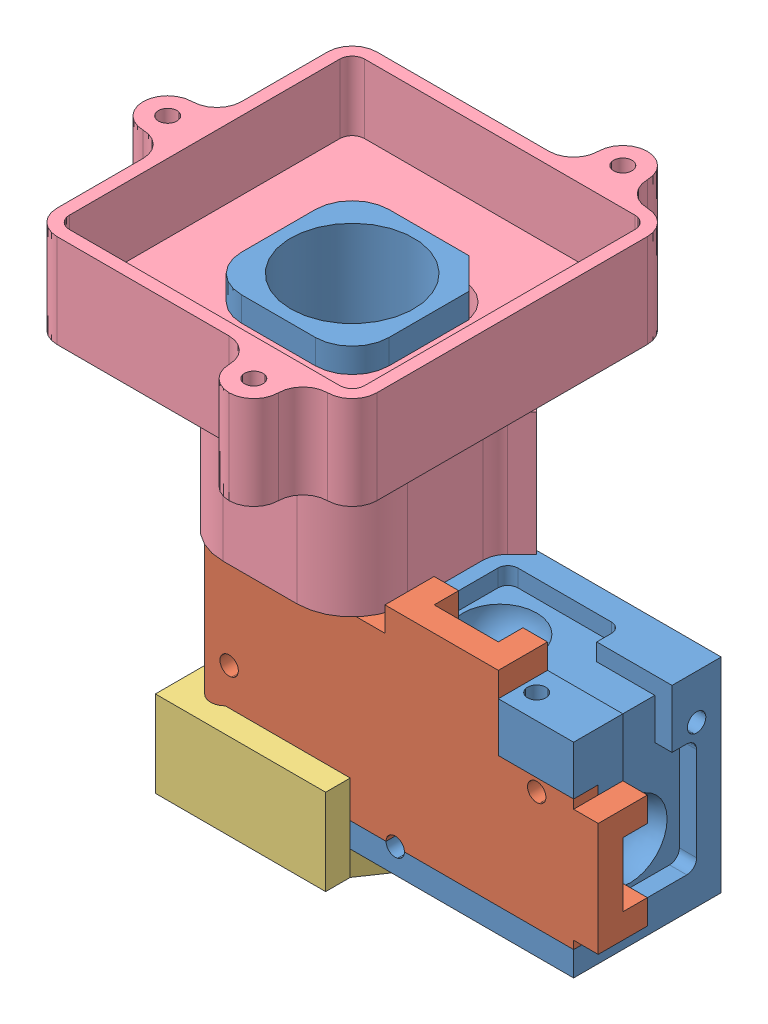
SolidWorks assembly OptoGscope_v1_0.4_Assembled, configuration Default. Lengths in mm.
Overall size (21.5 20.1 17).
4 component instances, 4 part files, 9 mates.
Components (placement in the parent):
- OGS_MainBodyv1_0.4-1: OGS_MainBodyv1_0.4 [Default] at (44.133 -21.7269 -14.4042) size (15 17.3 6)
- FilterCoverV5-1: FilterCoverV5 [Default] at (46.0384 -17.2404 -11.4042) x (-1 0 0) z (0 0 -1) size (16 8.3 2)
- MS_Baseplatev3-1: MS_Baseplatev3 [Default] at (41.383 -22.7269 -14.6542) x (0 0 1) z (-1 0 0) size (9.02 3.5 12.54)
- MS_FocusSliderv3.2-1: MS_FocusSliderv3.2 [Default] at (39.633 -13.4269 -14.4042) size (15 10.8 17)
Mates (geometry in assembly coordinates):
- Concentric1: concentric aligned: cylinder of OGS_MainBodyv1_0.4-1 through (38.133 -15.5482 -12.9042) axis (0 1 0) radius 1.5; cylinder of MS_FocusSliderv3.2-1 through (38.133 -2.6269 -12.9042) axis (0 1 0) radius 1.5
- Concentric2: concentric anti-aligned: cylinder of OGS_MainBodyv1_0.4-1 through (38.133 -13.4269 -15.9042) axis (0 -1 0) radius 1.5; cylinder of MS_FocusSliderv3.2-1 through (38.133 -2.6269 -15.9042) axis (0 1 0) radius 1.5
- Coincident1: coincident anti-aligned: plane of OGS_MainBodyv1_0.4-1 through (44.133 -13.4269 -14.4042) normal (0 1 0); plane of MS_FocusSliderv3.2-1 through (39.633 -13.4269 -14.4042) normal (0 -1 0)
- Concentric3: concentric anti-aligned: cylinder of OGS_MainBodyv1_0.4-1 through (50.133 -15.9269 -11.4041) axis (0 0 -1) radius 0.375; cylinder of FilterCoverV5-1 through (50.133 -15.9269 -12.4042) axis (0 0 1) radius 0.375
- Concentric4: concentric anti-aligned: cylinder of OGS_MainBodyv1_0.4-1 through (37.633 -17.7269 -11.4041) axis (0 0 -1) radius 0.375; cylinder of FilterCoverV5-1 through (37.633 -17.7269 -12.4042) axis (0 0 1) radius 0.375
- Coincident2: coincident anti-aligned: plane of OGS_MainBodyv1_0.4-1 through (44.133 -21.7269 -12.4042) normal (0 0 1); plane of FilterCoverV5-1 through (46.0384 -17.2404 -12.4042) normal (0 0 -1)
- Coincident3: coincident: plane of OGS_MainBodyv1_0.4-1 through (36.633 -13.4269 -17.4042) normal (-1 0 0); plane of MS_Baseplatev3-1 through (36.633 -34.7345 -11.4042) normal (1 0 0)
- Coincident4: coincident: plane of OGS_MainBodyv1_0.4-1 through (51.633 -13.4269 -11.4042) normal (0 0 1); plane of MS_Baseplatev3-1 through (46.133 -34.7345 -11.4042) normal (0 0 -1)
- Coincident5: coincident anti-aligned: plane of OGS_MainBodyv1_0.4-1 through (44.133 -21.7269 -14.4042) normal (0 -1 0); plane of MS_Baseplatev3-1 through (41.383 -21.7269 -14.6542) normal (0 1 0)
